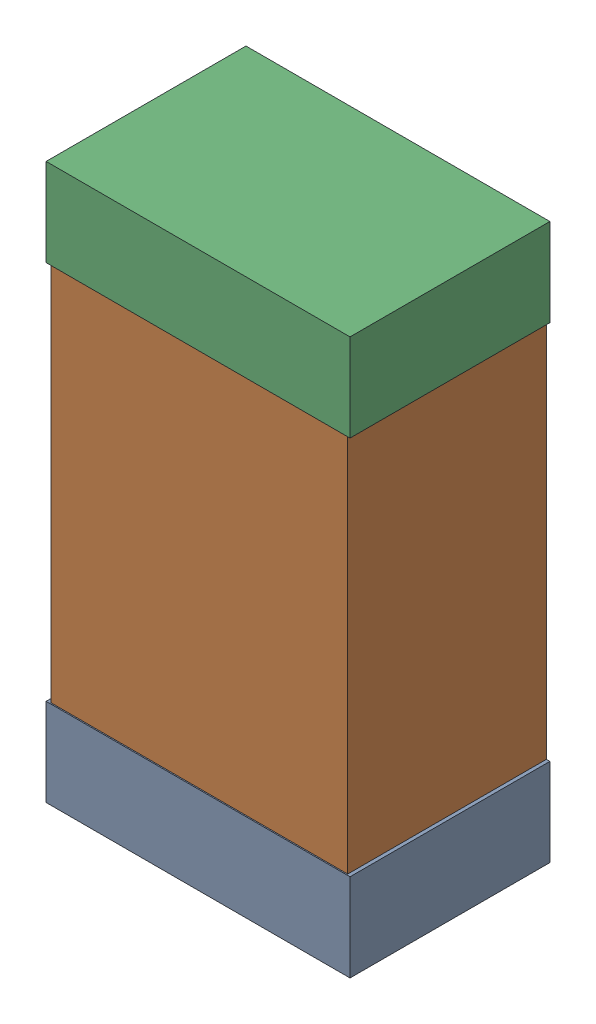
SolidWorks assembly 130kKanaloa_v2.0.0_Power, configuration Default. Lengths in mm.
Overall size (1.3 2.38 0.85).
6 component instances, 2 part files, 0 mates.
Components (placement in the parent):
- 330415056-1: 330415056 [Default] at (148.4768 92.2354 0) size (1.3 0.38 0.85)
  - Extruded_2-1: Extruded_2 [Default] at origin size (1.3 0.38 0.85)
- 334787376-1: 334787376 [Default] at (148.4768 93.2354 0) size (1.27 2.2 0.85)
  - Extruded_16-1: Extruded_16 [Default] at origin size (1.27 2.2 0.85)
- 330415056-2: 330415056 [Default] at (148.4768 94.2354 0) size (1.3 0.38 0.85)
  - Extruded_2-1: Extruded_2 [Default] at origin size (1.3 0.38 0.85)
